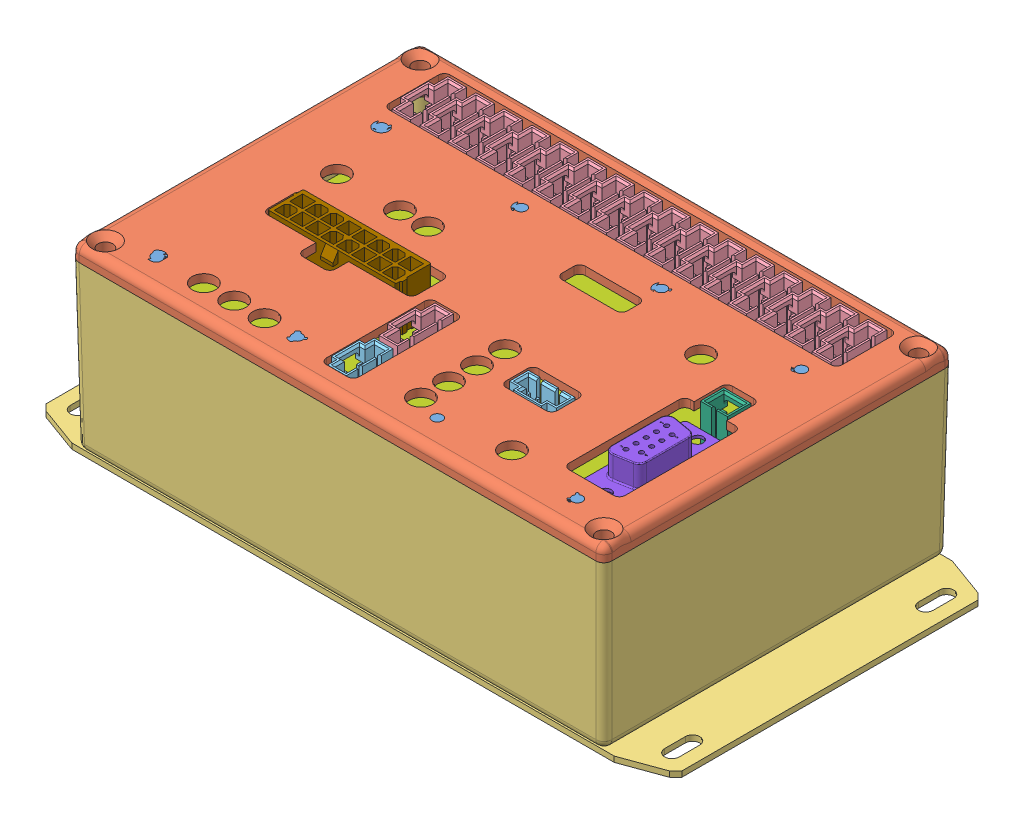
SolidWorks assembly BMS Controller, configuration Default. Lengths in mm.
Overall size (172.97 52.31 95).
35 component instances, 9 part files, 0 mates.
Components (placement in the parent):
- 1590J Lid - Modified-1: 1590J Lid - Modified [Default] at (0 46.5 0) size (145 6.56 95)
  - PEM FHS-440-4ZI-1: PEM FHS-440-4ZI [Default] at (57.15 4 -21.59) x (0 -1 0) z (0 0 1) size (6.35 4.47 4.47)
  - PEM FHS-440-4ZI-2: PEM FHS-440-4ZI [Default] at (-19.05 4 -21.59) x (0 -1 0) z (0 0 1) size (6.35 4.47 4.47)
  - 1590J Lid-1: 1590J Lid [Default] x (1 0 0) z (0 -1 0) size (145 95 6.25)
  - PEM FHS-440-4ZI-3: PEM FHS-440-4ZI [Default] at (57.15 4 39.37) x (0 -1 0) z (0 0 1) size (6.35 4.47 4.47)
  - PEM FHS-440-4ZI-4: PEM FHS-440-4ZI [Default] at (-57.15 4 -21.59) x (0 -1 0) z (0 0 1) size (6.35 4.47 4.47)
  - PEM FHS-440-4ZI-5: PEM FHS-440-4ZI [Default] at (19.05 4 -21.59) x (0 -1 0) z (0 0 1) size (6.35 4.47 4.47)
  - PEM FHS-440-4ZI-6: PEM FHS-440-4ZI [Default] at (-19.05 4 39.37) x (0 -1 0) z (0 0 1) size (6.35 4.47 4.47)
  - PEM FHS-440-4ZI-7: PEM FHS-440-4ZI [Default] at (19.05 4 39.37) x (0 -1 0) z (0 0 1) size (6.35 4.47 4.47)
  - PEM FHS-440-4ZI-8: PEM FHS-440-4ZI [Default] at (-57.15 4 39.37) x (0 -1 0) z (0 0 1) size (6.35 4.47 4.47)
- 1590JF Box-1: 1590JF Box [Default] at (0 46.5 0) x (1 0 0) z (0 1 0) size (172.97 95 46.5)
- BMS Controller Board-1: BMS Controller Board [Default] at (0 37.9813 0) size (127 17.25 88.9)
  - Molex 705430004-1: Molex 705430004 [Default] at (-34.417 6.8898 -34.7726) x (0 0 -1) z (0 1 0) size (15.24 6.6 15.11)
  - Molex 705430004-2: Molex 705430004 [Default] at (-26.797 6.8898 -34.7726) x (0 0 -1) z (0 1 0) size (15.24 6.6 15.11)
  - Molex 705430004-3: Molex 705430004 [Default] at (-42.037 6.8898 -34.7726) x (0 0 -1) z (0 1 0) size (15.24 6.6 15.11)
  - Molex 705430004-4: Molex 705430004 [Default] at (49.403 6.8898 -34.7726) x (0 0 -1) z (0 1 0) size (15.24 6.6 15.11)
  - Molex 705430004-5: Molex 705430004 [Default] at (-57.277 6.8898 -34.7726) x (0 0 -1) z (0 1 0) size (15.24 6.6 15.11)
  - Molex 705430003-1: Molex 705430003 [Default] at (-5.715 6.8898 35.56) x (0 0 -1) z (0 1 0) size (12.7 6.6 15.11)
  - Molex 705430004-6: Molex 705430004 [Default] at (-49.657 6.8898 -34.7726) x (0 0 -1) z (0 1 0) size (15.24 6.6 15.11)
  - Molex 705430004-7: Molex 705430004 [Default] at (-3.937 6.8898 -34.7726) x (0 0 -1) z (0 1 0) size (15.24 6.6 15.11)
  - Molex 705430004-8: Molex 705430004 [Default] at (41.783 6.8898 -34.7726) x (0 0 -1) z (0 1 0) size (15.24 6.6 15.11)
  - Molex 705430003-2: Molex 705430003 [Default] at (26.67 6.8898 18.415) x (-1 0 0) z (0 1 0) size (12.7 6.6 15.11)
  - Molex 705430004-9: Molex 705430004 [Default] at (34.163 6.8898 -34.7726) x (0 0 -1) z (0 1 0) size (15.24 6.6 15.11)
  - Molex 705430004-10: Molex 705430004 [Default] at (-11.557 6.8898 -34.7726) x (0 0 -1) z (0 1 0) size (15.24 6.6 15.11)
  - Molex 705430004-11: Molex 705430004 [Default] at (3.683 6.8898 -34.7726) x (0 0 -1) z (0 1 0) size (15.24 6.6 15.11)
  - Molex 705430001-1: Molex 705430001 [Default] at (54.6354 6.8898 -2.8448) x (1 0 0) z (0 1 0) size (7.37 6.35 15.11)
  - Molex 705430004-12: Molex 705430004 [Default] at (18.923 6.8898 -34.7726) x (0 0 -1) z (0 1 0) size (15.24 6.6 15.11)
  - Molex 705430004-13: Molex 705430004 [Default] at (-19.177 6.8898 -34.7726) x (0 0 -1) z (0 1 0) size (15.24 6.6 15.11)
  - Molex 705430004-14: Molex 705430004 [Default] at (57.023 6.8898 -34.7726) x (0 0 -1) z (0 1 0) size (15.24 6.6 15.11)
  - Molex 705430004-15: Molex 705430004 [Default] at (11.303 6.8898 -34.7726) x (0 0 -1) z (0 1 0) size (15.24 6.6 15.11)
  - Molex 705430004-16: Molex 705430004 [Default] at (26.543 6.8898 -34.7726) x (0 0 -1) z (0 1 0) size (15.24 6.6 15.11)
  - Lithiumate Board-1: Lithiumate Board [Default] at origin size (127 1.59 88.9)
  - NorComp 171-009-213-1: NorComp 171-009-213 [Default] at (61.5696 8.1852 32.6898) x (0 0 -1) z (0 1 0) size (30.81 12.6 17.25)
  - Molex 705430004-17: Molex 705430004 [Default] at (-5.715 6.8898 20.32) x (0 0 -1) z (0 1 0) size (15.24 6.6 15.11)
  - Molex 039281163-1: Molex 039281163 [Default] at (-34.5176 0.7937 9.6526) size (35.6 16.3 11)
